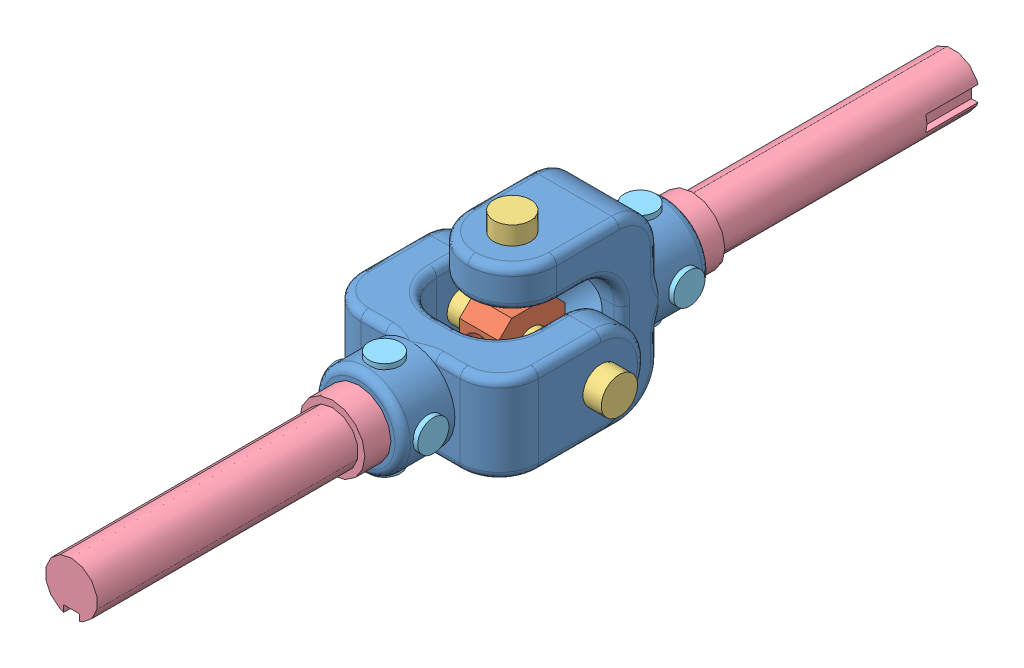
SolidWorks assembly minor 1, configuration Default. Lengths in mm.
Overall size (82.08 82 338).
17 component instances, 5 part files, 34 mates.
Components (placement in the parent):
- fork-1: fork [Default] at (41.3744 12.2108 38.5146) x (-1 0 0) z (0 1 0) size (68 76 34)
- fork-2: fork [Default] at (24.3744 -4.7892 72.5146) x (0 1 0) z (-1 0 0) size (68 76 34)
- nut-1: nut [Default] at (-0.1256 16.5108 68.2146) x (0 0 -1) z (1 0 0) size (25.4 25.4 15)
- bolt joint-1: bolt joint [Default] at (48.4573 29.2108 55.5146) x (0 -0.672364 -0.740221) z (-1 0 0) size (14 14 40)
- bolt joint-2: bolt joint [Default] at (7.3744 70.2108 55.5146) x (-0.087264 0 0.996185) z (0 -1 0) size (14 14 40)
- bolt joint-3: bolt joint [Default] at (7.3744 -11.7892 55.5146) x (1 0 0) z (0 1 0) size (14 14 40)
- bolt joint-4: bolt joint [Default] at (-33.6256 29.2108 55.5146) x (0 -1 0) z (1 0 0) size (14 14 40)
- shaft-1: shaft [Default] at (7.3744 29.2108 224.5146) x (0 -1 0) z (0 0 -1) size (25 25 130)
- shaft-2: shaft [Default] at (7.3744 29.2108 -113.4854) size (25 25 130)
- pin-9: pin [Default] at (7.3744 48.1594 6.5146) x (0.867943 0 0.496663) z (0 -1 0) size (12 12 12)
- pin-10: pin [Default] at (-11.5908 29.2108 6.5146) x (0 0.09623 0.995359) z (1 0 0) size (12 12 12)
- pin-11: pin [Default] at (7.3744 10.1928 6.5146) x (-0.944249 0 -0.329233) z (0 1 0) size (12 12 12)
- pin-12: pin [Default] at (26.2625 29.2108 6.5146) x (0 -0.801818 0.597568) z (-1 0 0) size (12 12 12)
- pin-13: pin [Default] at (26.1076 29.2108 104.5146) x (0 -0.88319 -0.469016) z (-1 0 0) size (12 12 12)
- pin-14: pin [Default] at (7.3744 10.2108 104.5146) x (-0.944249 0 -0.329233) z (0 1 0) size (12 12 12)
- pin-15: pin [Default] at (7.3744 47.944 104.5146) x (0.990411 0 0.138152) z (0 -1 0) size (12 12 12)
- pin-16: pin [Default] at (-11.3588 29.2108 104.5146) x (0 -0.989373 0.1454) z (1 0 0) size (12 12 12)
Mates (geometry in assembly coordinates):
- Concentric1: concentric aligned: circle of fork-1; circle of nut-1
- Concentric2: concentric anti-aligned: circle of fork-1; circle of nut-1
- Concentric3: concentric aligned: circle of fork-2; circle of nut-1
- Concentric4: concentric aligned: circle of fork-2; circle of nut-1
- Concentric5: concentric anti-aligned: circle of fork-1; circle of bolt joint-1
- Concentric6: concentric anti-aligned: circle of fork-1; circle of bolt joint-1
- Concentric7: concentric anti-aligned: circle of fork-1; circle of bolt joint-1
- Concentric8: concentric anti-aligned: circle of fork-1; circle of bolt joint-1
- Lock1: lock: unknown of nut-1; unknown of bolt joint-1
- Coincident6: coincident anti-aligned: circle of fork-1; circle of bolt joint-4
- Coincident8: coincident anti-aligned: circle of fork-2; circle of bolt joint-2
- Coincident9: coincident anti-aligned: circle of fork-2; circle of bolt joint-3
- Concentric16: concentric anti-aligned: cylinder of fork-2 through (7.3744 -20.7892 6.5146) axis (0 1 0) radius 3; circle of pin-9
- Lock2: lock: unknown of fork-2; unknown of pin-9
- Concentric18: concentric aligned: cylinder of fork-2 through (74.3744 29.2108 6.5146) axis (-1 0 0) radius 3; cylinder of pin-10 through (0.4092 29.2108 6.5146) axis (-1 0 0) radius 3
- Concentric19: concentric anti-aligned: cylinder of fork-2 through (7.3744 -20.7892 6.5146) axis (0 1 0) radius 3; cylinder of pin-11 through (7.3744 22.1928 6.5146) axis (0 -1 0) radius 3
- Lock3: lock: unknown of pin-10; unknown of pin-11
- Lock4: lock: unknown of pin-10; unknown of pin-11
- Concentric22: concentric anti-aligned: cylinder of fork-2 through (74.3744 29.2108 6.5146) axis (-1 0 0) radius 3; cylinder of pin-12 through (14.2625 29.2108 6.5146) axis (1 0 0) radius 3
- Lock5: lock: unknown of fork-2; unknown of pin-12
- Concentric24: concentric anti-aligned: circle of fork-2; circle of shaft-2
- Coincident17: coincident anti-aligned: circle of fork-2; circle of shaft-2
- Perpendicular4: perpendicular: line of fork-2 through (-6.6256 10.2108 16.5146) axis (1 0 0); line of shaft-2 through (14.3744 26.2108 -113.4854) axis (0 1 0)
- Concentric25: concentric aligned: cylinder of fork-1 through (7.3744 -37.7892 104.5146) axis (0 1 0) radius 3; cylinder of pin-15 through (7.3744 35.944 104.5146) axis (0 1 0) radius 3
- Tangent13: tangent: curve of fork-1; circle of pin-15
- Concentric26: concentric anti-aligned: cylinder of fork-1 through (57.3744 29.2108 104.5146) axis (-1 0 0) radius 3; cylinder of pin-13 through (14.1076 29.2108 104.5146) axis (1 0 0) radius 3
- Tangent14: tangent: edge_curve of fork-1; circle of pin-13
- Concentric27: concentric anti-aligned: cylinder of fork-1 through (7.3744 -37.7892 104.5146) axis (0 1 0) radius 3; cylinder of pin-14 through (7.3744 22.2108 104.5146) axis (0 -1 0) radius 3
- Tangent15: tangent: edge_curve of fork-1; circle of pin-14
- Concentric28: concentric aligned: cylinder of fork-1 through (57.3744 29.2108 104.5146) axis (-1 0 0) radius 3; cylinder of pin-16 through (0.6412 29.2108 104.5146) axis (-1 0 0) radius 3
- Tangent16: tangent: edge_curve of fork-1; circle of pin-16
- Concentric29: concentric anti-aligned: circle of fork-1; circle of shaft-1
- Coincident19: coincident anti-aligned: plane of fork-1 through (7.3744 29.2108 114.5146) normal (0 0 1); circle of shaft-1
- Parallel8: parallel anti-aligned: line of fork-1 through (17.018 15.2108 94.5146) axis (1 0 0); line of shaft-1 through (10.3744 22.2108 224.5146) axis (-1 0 0)
